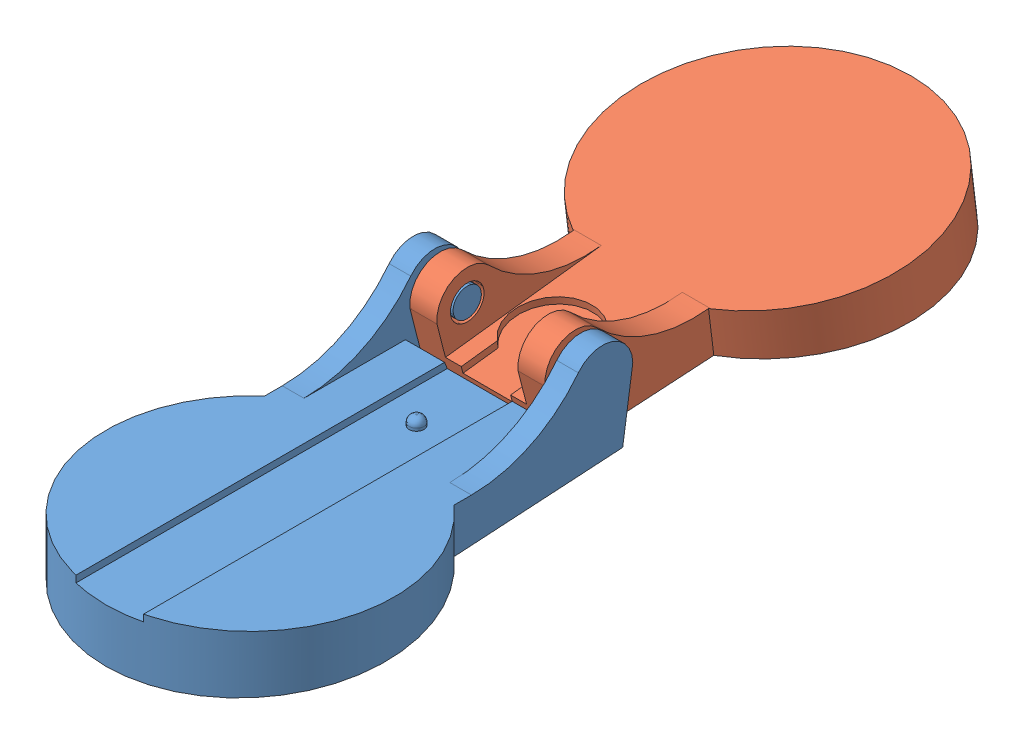
SolidWorks assembly Assem2, configuration Default. Lengths in mm.
Overall size (21.37 12.99 60.12).
2 component instances, 2 part files, 2 mates.
Components (placement in the parent):
- baseOutside-1: baseOutside [Default] at (8.5257 9.6369 26.6619) size (21.37 9.19 32)
- baseInside-1: baseInside [Default] at (8.5257 11.2333 0.3487) x (-1 0 0) z (0 0.120892 -0.992666) size (21.37 9.19 32)
Mates (geometry in assembly coordinates):
- Concentric1: concentric aligned: circle of baseOutside-1; circle of baseInside-1
- Tangent1: tangent: plane of baseOutside-1 through (5.5257 17.1369 13.9119) normal (1 0 0); circle of baseInside-1
